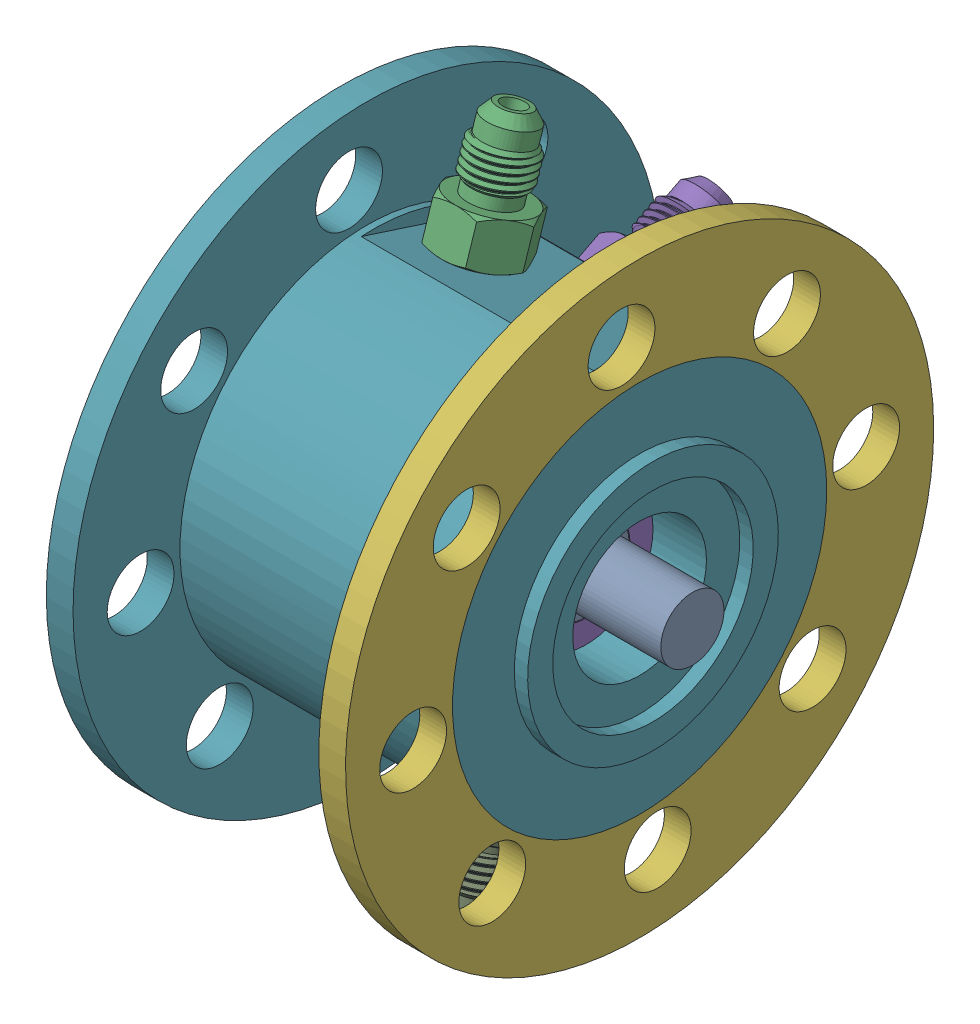
SolidWorks assembly IPS_assembly, configuration Default. Lengths in mm.
Overall size (77.22 140.74 140.74).
12 component instances, 7 part files, 16 mates.
Components (placement in the parent):
- shaft_seal_section-1: shaft_seal_section [Default] at origin size (77.22 19.05 19.05)
- 7201_cd_hcp4a-1: 7201_cd_hcp4a [Default] at (20.32 0 0) x (-1 0 0) z (0 -0.924225 -0.381849) size (10 32 32)
  - 7201_cd_hcp4a_01-1: 7201_cd_hcp4a_01 [Default] at origin size (10 32 32)
  - 7201_cd_hcp4a_02-1: 7201_cd_hcp4a_02 [Default] at origin size (10 18.6 18.6)
  - 7201_cd_hcp4a_03-1: 7201_cd_hcp4a_03 [Default] at origin size (5.56 27.56 26.48)
- Seal_insert-3: Seal_insert [Default] at (26.797 0 0) size (36.7 30.1 30.1)
- IPS_Casing2-1: IPS_Casing2 [Default] at (10.32 0 0) x (1 0 0) z (0 -0.307937 -0.951407) size (61.94 111.76 111.76)
- orb to -4an fitting-1: orb to -4an fitting [50715K831] at (51.181 -37.5777 12.1626) x (0.18244 0.302769 0.935439) z (0 -0.951407 0.307937) size (14.29 16.5 31.43)
- orb to -4an fitting-2: orb to -4an fitting [50715K831] at (44.958 -35.1717 -17.9712) x (0.467597 0.402195 -0.787142) z (0 -0.89049 -0.455002) size (14.29 16.5 31.43)
- orb to -4an fitting-3: orb to -4an fitting [50715K831] at (38.735 -12.1626 -37.5777) x (0.986737 -0.154436 0.049986) z (0 -0.307937 -0.951407) size (14.29 16.5 31.43)
- orb to -4an fitting-4: orb to -4an fitting [50715K831] at (26.289 37.5777 -12.1626) x (0.871385 0.151074 0.466761) z (0 0.951407 -0.307937) size (14.29 16.5 31.43)
- orb to -4an fitting-5: orb to -4an fitting [50715K831] at (32.512 17.9712 -35.1717) x (1 0 0) z (0 0.455002 -0.89049) size (14.29 16.5 31.43)
Mates (geometry in assembly coordinates):
- Concentric7: concentric aligned: cylinder of shaft_seal_section-1 through (0 0 0) axis (-1 0 0) radius 6; cylinder of 7201_cd_hcp4a-1/7201_cd_hcp4a_02-1 through (15.32 0 0) axis (-1 0 0) radius 6
- Concentric9: concentric aligned: cylinder of shaft_seal_section-1 through (0 0 0) axis (-1 0 0) radius 9.017; cylinder of Seal_insert-3 through (26.797 0 0) axis (-1 0 0) radius 9.5758
- Concentric10: concentric anti-aligned: cylinder of 7201_cd_hcp4a-1/7201_cd_hcp4a_01-1 through (15.17 0 0) axis (-1 0 0) radius 16; cylinder of IPS_Casing2-1 through (10.32 0 0) axis (1 0 0) radius 16
- Coincident1: coincident anti-aligned: plane of Seal_insert-3 through (57.023 15.0495 0) normal (1 0 0); plane of IPS_Casing2-1 through (57.023 -14.4994 4.693) normal (-1 0 0)
- Coincident2: coincident anti-aligned: plane of 7201_cd_hcp4a-1/7201_cd_hcp4a_01-1 through (20.32 5.4795 -13.2626) normal (1 0 0); plane of IPS_Casing2-1 through (20.32 -14.4994 4.693) normal (-1 0 0)
- Coincident3: coincident anti-aligned: plane of shaft_seal_section-1 through (51.689 8.255 0) normal (1 0 0); plane of Seal_insert-3 through (51.689 8.3058 0) normal (-1 0 0)
- Concentric14: concentric aligned: cylinder of IPS_Casing2-1 through (51.181 -14.4994 4.693) axis (0 0.951407 -0.307937) radius 4.9609; cylinder of orb to -4an fitting-1 through (51.181 -22.7158 7.3523) axis (0 0.951407 -0.307937) radius 2.159
- Concentric15: concentric aligned: cylinder of IPS_Casing2-1 through (44.958 -13.5711 -6.9342) axis (0 0.89049 0.455002) radius 2.159; cylinder of orb to -4an fitting-2 through (44.958 -21.2613 -10.8636) axis (0 0.89049 0.455002) radius 2.159
- Concentric16: concentric aligned: circle of IPS_Casing2-1; circle of orb to -4an fitting-3
- Concentric17: concentric aligned: circle of IPS_Casing2-1; circle of orb to -4an fitting-5
- Concentric18: concentric aligned: cylinder of IPS_Casing2-1 through (26.289 14.4994 -4.693) axis (0 -0.951407 0.307937) radius 4.9609; circle of orb to -4an fitting-4
- Coincident4: coincident anti-aligned: plane of IPS_Casing2-1 through (10.32 -10.1681 -31.4155) normal (0 -0.307937 -0.951407); plane of orb to -4an fitting-3 through (38.735 -10.1681 -31.4155) normal (0 0.307937 0.951407)
- Coincident5: coincident anti-aligned: plane of IPS_Casing2-1 through (10.32 15.0242 -29.404) normal (0 0.455002 -0.89049); plane of orb to -4an fitting-5 through (32.512 15.0242 -29.404) normal (0 -0.455002 0.89049)
- Coincident6: coincident anti-aligned: plane of IPS_Casing2-1 through (10.32 31.4155 -10.1681) normal (0 0.951407 -0.307937); plane of orb to -4an fitting-4 through (26.289 31.4155 -10.1681) normal (0 -0.951407 0.307937)
- Coincident7: coincident anti-aligned: plane of IPS_Casing2-1 through (10.32 -29.404 -15.0242) normal (0 -0.89049 -0.455002); plane of orb to -4an fitting-2 through (44.958 -29.404 -15.0242) normal (0 0.89049 0.455002)
- Coincident8: coincident anti-aligned: plane of IPS_Casing2-1 through (10.32 -31.4155 10.1681) normal (0 -0.951407 0.307937); plane of orb to -4an fitting-1 through (51.181 -31.4155 10.1681) normal (0 0.951407 -0.307937)
